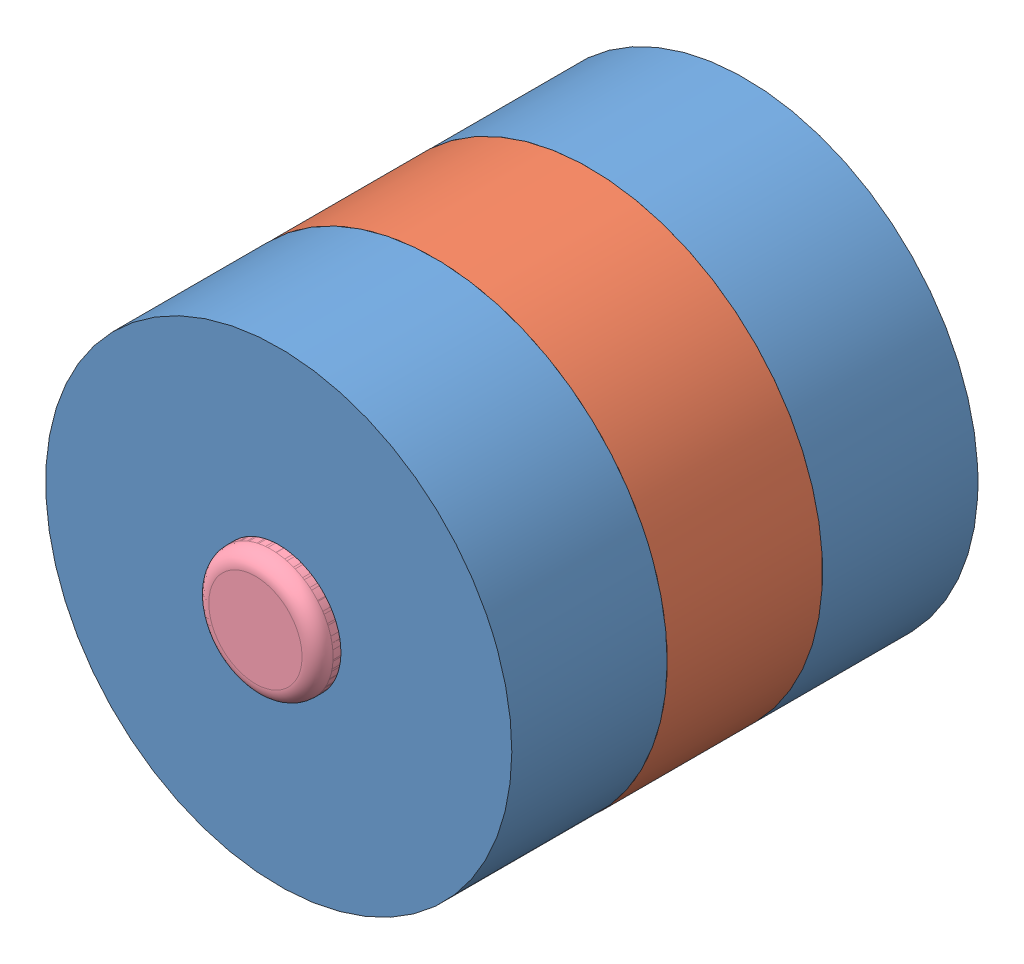
SolidWorks assembly Sparkgap, configuration Standard. Lengths in mm.
Overall size (39.48 39.48 39).
5 component instances, 4 part files, 10 mates.
Components (placement in the parent):
- Sparkgapcover-1: Sparkgapcover [Standard] at (-1.992 1.2948 25) size (30 30 10)
- Sparkgapcenter-1: Sparkgapcenter [Standard] at (-1.992 1.2948 40) size (29.14 30 10)
- Sparkgapcover-2: Sparkgapcover [Standard] at (-1.992 1.2948 55) x (0.916845 0.399243 0) z (0 0 -1) size (30 30 10)
- Sparkgap electrode2-1: Sparkgap electrode2 [Standard] at (-1.992 1.2948 17.5) x (0.76076 0.649033 0) z (0 0 1) size (8 8 22)
- Sparkgap electrode-1: Sparkgap electrode [Standard] at (-1.992 1.2948 56.5) x (0.983227 0.182384 0) z (0 0 -1) size (8 8 15)
Mates (geometry in assembly coordinates):
- Konzentrisch1: concentric aligned: cylinder of Sparkgapcover-1 through (-1.992 1.2948 35) axis (0 0 -1) radius 15; cylinder of Sparkgapcenter-1 through (-1.992 1.2948 45) axis (0 0 -1) radius 15
- Konzentrisch3: concentric anti-aligned: cylinder of Sparkgapcover-1 through (-1.992 1.2948 35) axis (0 0 -1) radius 3.35; cylinder of Sparkgap electrode1-1 through (-1.992 1.2948 53.2689) axis (0 0 1) radius 4
- Konzentrisch4: concentric aligned: cylinder of Sparkgapcover-1 through (-1.992 1.2948 35) axis (0 0 -1) radius 3.35; cylinder of Sparkgap electrode2-1 through (-1.992 1.2948 39.5) axis (0 0 -1) radius 4
- Parallel1: parallel anti-aligned: plane of Sparkgapcenter-1 through (-16.1341 6.2948 35) normal (-1 0 0)
- Deckungsgleich2: coincident anti-aligned: plane of Sparkgapcover-1 through (-1.992 1.2948 35) normal (0 0 1); plane of Sparkgapcenter-1 through (-1.992 1.2948 35) normal (0 0 -1)
- Deckungsgleich3: coincident anti-aligned: plane of Sparkgapcenter-1 through (-1.992 1.2948 45) normal (0 0 1); plane of Sparkgapcover-2 through (-1.992 1.2948 45) normal (0 0 -1)
- Konzentrisch5: concentric anti-aligned: cylinder of Sparkgapcenter-1 through (-1.992 1.2948 45) axis (0 0 -1) radius 15; cylinder of Sparkgapcover-2 through (-1.992 1.2948 45) axis (0 0 1) radius 15
- Konzentrisch6: concentric aligned: cylinder of Sparkgapcover-2 through (-1.992 1.2948 45) axis (0 0 1) radius 3.35; cylinder of Sparkgap electrode-1 through (-1.992 1.2948 41.5) axis (0 0 1) radius 4
- Abstand1: distance = 1.5 mm aligned: plane of Sparkgap electrode-1 through (-1.992 1.2948 56.5) normal (0 0 1); plane of Sparkgapcover-2 through (-1.992 1.2948 55) normal (0 0 1)
- Abstand2: distance = 2 mm anti-aligned: plane of Sparkgap electrode-1 through (-1.992 1.2948 41.5) normal (0 0 -1); plane of Sparkgap electrode2-1 through (-1.992 1.2948 39.5) normal (0 0 1)
